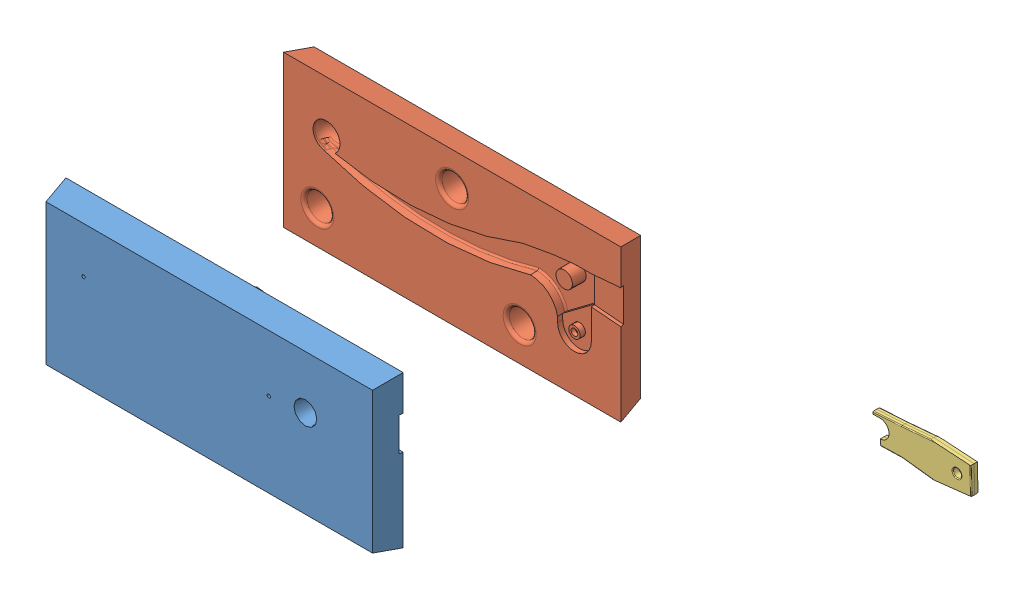
SolidWorks assembly Assem1, configuration Default. Lengths in mm.
Overall size (409.9 90 159.04).
3 component instances, 3 part files, 6 mates.
Components (placement in the parent):
- ghaleb bala-1: ghaleb bala [Default] at (-22.312 7.5025 6.6766) size (200 90 30)
- ghaleb paiin-1: ghaleb paiin [Default] at (-22.312 7.5025 -122.364) size (200 90 18)
- pin ja simi-1: pin ja simi [Default] at (263.7817 28.919 -122.364) x (-0.999675 -0.025512 0) z (0 0 -1) size (57.9 20 4)
Mates (geometry in assembly coordinates):
- Concentric1: concentric anti-aligned: cone of ghaleb bala-1 through (17.688 -17.4975 6.6766) axis (0 0 -1); circle of ghaleb paiin-1
- Concentric2: concentric anti-aligned: cone of ghaleb bala-1 through (-102.312 -17.4975 6.6766) axis (0 0 -1); circle of ghaleb paiin-1
- Parallel8: parallel anti-aligned: plane of ghaleb bala-1 through (58.9573 29.9373 8.6766) normal (0 0 -1); plane of pin ja simi-1 through (233.4163 38.1473 -120.364) normal (0 0 1)
- Parallel9: parallel anti-aligned: plane of ghaleb paiin-1 through (77.688 31.5025 -124.364) normal (0 0 1); plane of pin ja simi-1 through (233.4163 38.1473 -124.364) normal (0 0 -1)
- Coincident23: coincident anti-aligned: line of ghaleb paiin-1 through (77.688 31.5025 -122.364) axis (-0.996347 -0.085401 0); line of pin ja simi-1 through (246.2215 45.9483 -122.364) axis (0.996347 0.085401 0)
- Parallel11: parallel anti-aligned: plane of ghaleb bala-1 through (58.9573 29.9373 8.6766) normal (0 0 -1); plane of pin ja simi-1 through (233.4163 38.1473 -120.364) normal (0 0 1)
